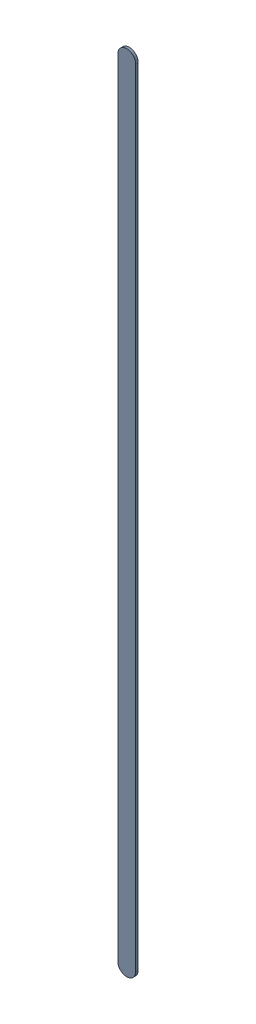
SolidWorks assembly Track (31.8mm,40.7mm)(31.8mm,51.8mm) on Top Layer, configuration Predeterminado. Lengths in mm.
Overall size (0.25 11.35 0.04).
2 component instances, 1 part files, 0 mates.
Components (placement in the parent):
- Track (31.8mm,40.7mm)(31.8mm,51.8mm) on Top Layer-1-1: Track (31.8mm,40.7mm)(31.8mm,51.8mm) on Top Layer-1 [Predeterminado] at (-68.317 -44.187 -0.0457) size (0.25 11.35 0.04)
  - Track (31.8mm,40.7mm)(31.8mm,51.8mm) on Top Layer-Part-1-1: Track (31.8mm,40.7mm)(31.8mm,51.8mm) on Top Layer-Part-1 [Predeterminado] at origin size (0.25 11.35 0.04)
